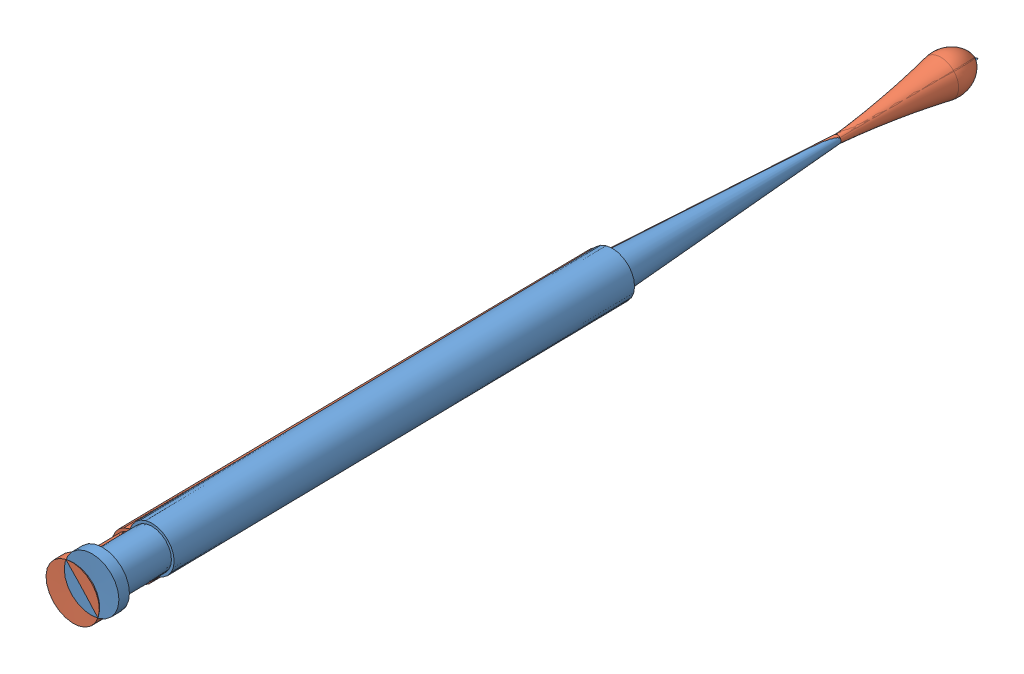
SolidWorks assembly Panetti left with tip reach volume_assem, configuration Default. Lengths in mm.
Overall size (12.24 12.39 125.47).
2 component instances, 2 part files, 1 mates.
Components (placement in the parent):
- Panetti left-1: Panetti left [Default] at (30.3983 55.8268 104.4605) size (8.08 7.5 125.43)
- Panetti left with tip reach volume-1: Panetti left with tip reach volume [Default] at (27.7494 35.8009 76.2602) x (-0.741519 -0.670918 -0.004349) z (0.004307 -0.011242 0.999928) size (8.08 7.5 125.34)
Mates (geometry in assembly coordinates):
- Coincident2: coincident: circle of Panetti left-1; cone of Panetti left with tip reach volume-1 through (54.736 55.8268 54.677) axis (-0.01673 0 -0.99986)
